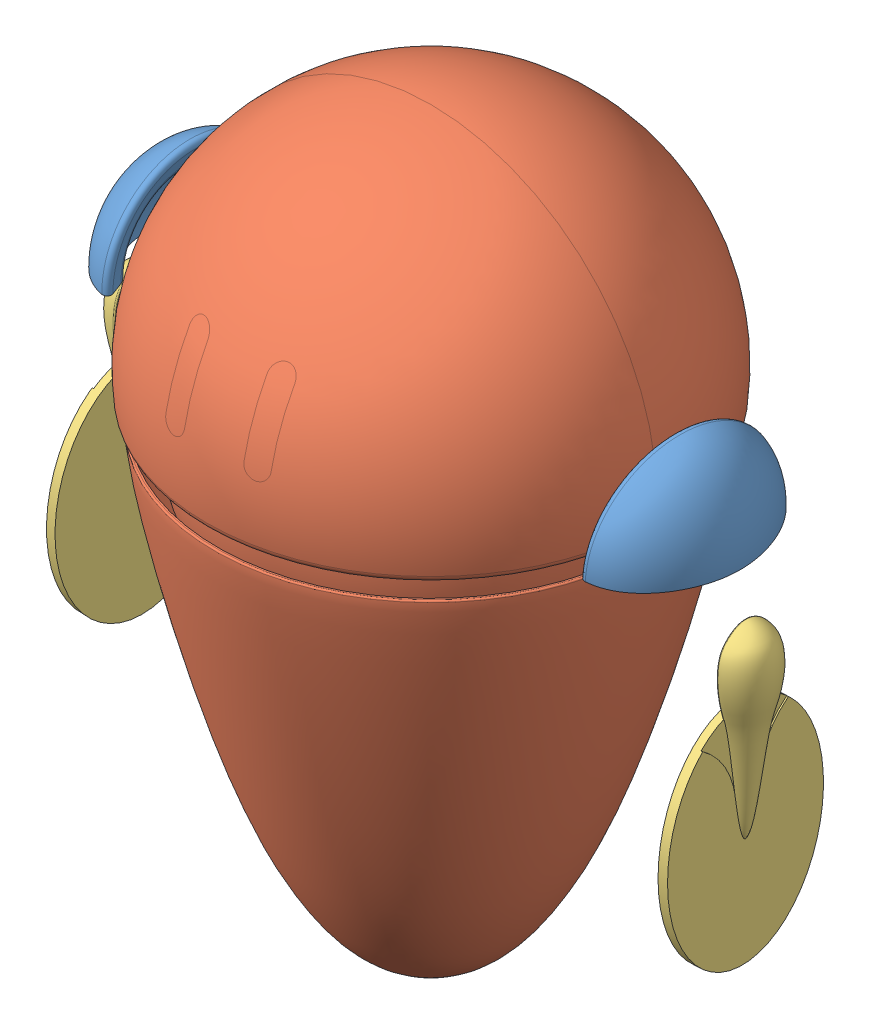
SolidWorks assembly Assemblage1, configuration Défaut. Lengths in mm.
Overall size (453.16 490.34 340).
5 component instances, 3 part files, 0 mates.
Components (placement in the parent):
- épaule-1: épaule [Défaut] at (-4.2977 2.2965 39.9219) x (0.996134 -0.065116 0.05897) z (-0.060075 -0.015135 0.998079) size (43.35 59.79 119.58)
- nono le robot-1: nono le robot [Défaut] at (-128.6322 -12.4104 44.8049) size (350.8 490.34 340)
- épaule-3: épaule [Défaut] at (-256.8189 -1.7984 36.5736) x (-0.999798 -0.01943 -0.00513) z (0.005268 -0.007103 -0.999961) size (43.35 59.79 119.58)
- raquette main-3: raquette main [Défaut] at (-331.7634 -138.1186 37.2486) x (0.052579 -0.065036 -0.996497) z (0.998616 0.002368 0.052536) size (110 200.7 25.47)
- raquette main-4: raquette main [Défaut] at (74.4297 -137.2661 39.8303) x (0.05611 0 0.998425) z (-0.998425 0 0.05611) size (110 200.7 25.47)
